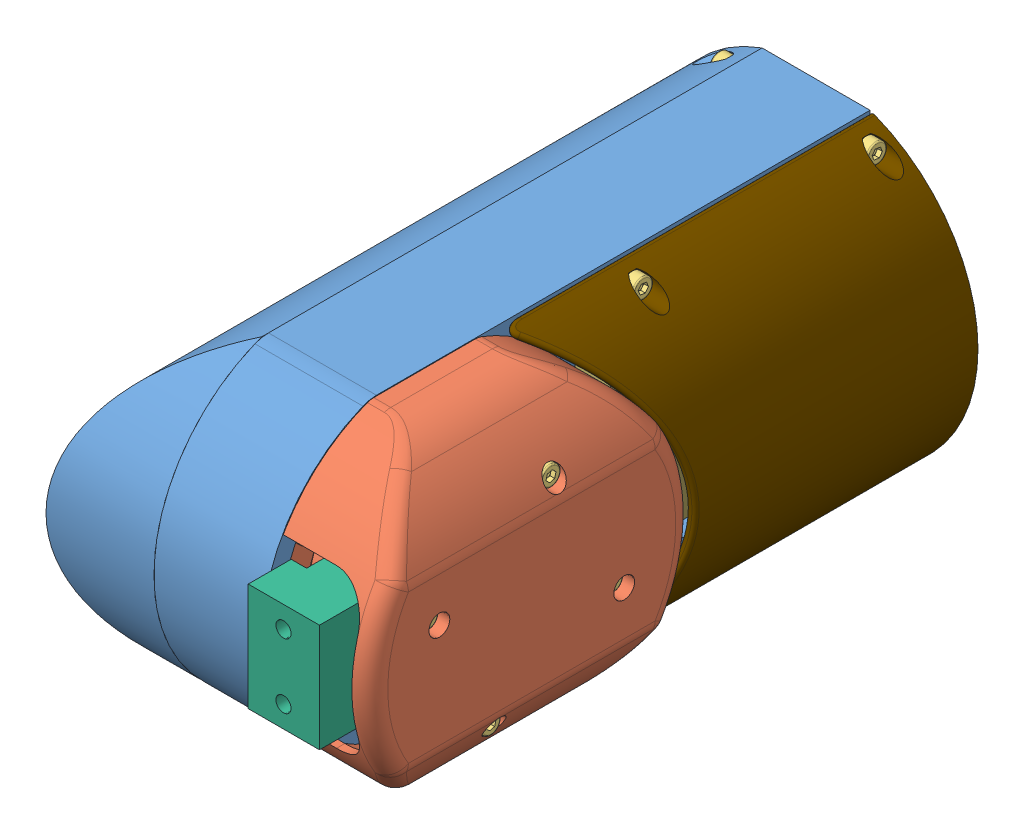
SolidWorks assembly 第二节, configuration 默认. Lengths in mm.
Overall size (169.08 108.07 185.47).
85 component instances, 22 part files, 108 mates.
Components (placement in the parent):
- 90001001-J2轴中间部件-1: 90001001-J2轴中间部件 [默认] at origin size (136.23 108.07 181.47)
- 90000013-SHF-17-80-2SH-SP刚柔轮组件-1: 90000013-SHF-17-80-2SH-SP刚柔轮组件 [默认] at (-7 0 205) x (0 1 0) z (1 0 0) size (80 80 29.5)
- hexagon socket head cap screws gb-1: hexagon socket head cap screws gb [GB_FASTENER_SCREWS_HSHCS M3X25-N] at (15 -37 205) x (-1 0 0) z (0 -0.763296 0.646049) size (28 5.5 5.5)
- hexagon socket head cap screws gb-2: hexagon socket head cap screws gb [GB_FASTENER_SCREWS_HSHCS M3X25-N] at (15 -32.0429 186.5) x (-1 0 0) z (0 -0.984058 0.177847) size (28 5.5 5.5)
- hexagon socket head cap screws gb-3: hexagon socket head cap screws gb [GB_FASTENER_SCREWS_HSHCS M3X25-N] at (15 -18.5 172.9571) x (-1 0 0) z (0 -0.941143 -0.338009) size (28 5.5 5.5)
- hexagon socket head cap screws gb-4: hexagon socket head cap screws gb [GB_FASTENER_SCREWS_HSHCS M3X25-N] at (15 0 168) x (-1 0 0) z (0 -0.646049 -0.763296) size (28 5.5 5.5)
- hexagon socket head cap screws gb-5: hexagon socket head cap screws gb [GB_FASTENER_SCREWS_HSHCS M3X25-N] at (15 18.5 172.9571) x (-1 0 0) z (0 -0.177847 -0.984058) size (28 5.5 5.5)
- hexagon socket head cap screws gb-6: hexagon socket head cap screws gb [GB_FASTENER_SCREWS_HSHCS M3X25-N] at (15 32.0429 186.5) x (-1 0 0) z (0 0.338009 -0.941143) size (28 5.5 5.5)
- hexagon socket head cap screws gb-7: hexagon socket head cap screws gb [GB_FASTENER_SCREWS_HSHCS M3X25-N] at (15 37 205) x (-1 0 0) z (0 0.763296 -0.646049) size (28 5.5 5.5)
- hexagon socket head cap screws gb-8: hexagon socket head cap screws gb [GB_FASTENER_SCREWS_HSHCS M3X25-N] at (15 32.0429 223.5) x (-1 0 0) z (0 0.984058 -0.177847) size (28 5.5 5.5)
- hexagon socket head cap screws gb-9: hexagon socket head cap screws gb [GB_FASTENER_SCREWS_HSHCS M3X25-N] at (15 18.5 237.0429) x (-1 0 0) z (0 0.941143 0.338009) size (28 5.5 5.5)
- hexagon socket head cap screws gb-10: hexagon socket head cap screws gb [GB_FASTENER_SCREWS_HSHCS M3X25-N] at (15 0 242) x (-1 0 0) z (0 0.646049 0.763296) size (28 5.5 5.5)
- hexagon socket head cap screws gb-11: hexagon socket head cap screws gb [GB_FASTENER_SCREWS_HSHCS M3X25-N] at (15 -18.5 237.0429) x (-1 0 0) z (0 0.177847 0.984058) size (28 5.5 5.5)
- hexagon socket head cap screws gb-12: hexagon socket head cap screws gb [GB_FASTENER_SCREWS_HSHCS M3X25-N] at (15 -32.0429 223.5) x (-1 0 0) z (0 -0.338009 0.941143) size (28 5.5 5.5)
- 90000013-SHF-17-80-2SH-SP波发生器-1: 90000013-SHF-17-80-2SH-SP波发生器 [默认] at (11.9 0 205) x (0 -0.338223 -0.941066) z (1 0 0) size (45 45 7.6)
- 90000009-J1轴减速机安装输出轴-1: 90000009-J1轴减速机安装输出轴 [默认] at (30.5 0 205) x (0 -0.338223 -0.941066) z (-1 0 0) size (27 27 62.5)
- hexagon socket head cap screws gb-13: hexagon socket head cap screws gb [GB_FASTENER_SCREWS_HSHCS M4X8-N] at (5.9 -3.7205 194.6483) size (12 7 7)
- hexagon socket head cap screws gb-14: hexagon socket head cap screws gb [GB_FASTENER_SCREWS_HSHCS M4X8-N] at (5.9 3.7205 215.3517) x (1 0 0) z (0 0 -1) size (12 7 7)
- 90000006-J1轴转接法兰-1: 90000006-J1轴转接法兰 [默认] at (0 0 160) x (0 -1 0) z (0 0 1) size (64 19.8 81.67)
- 90000012-轴承636-1: 90000012-轴承636 [默认] at (31 0 205) x (0 -1 0) z (-1 0 0) size (22 22 9)
- hexagon socket head cap screws gb-15: hexagon socket head cap screws gb [GB_FASTENER_SCREWS_HSHCS M3X20-N] at (30.5 15.8702 226.8435) x (-1 0 0) z (0 -0.924225 -0.381849) size (23 5.5 5.5)
- hexagon socket head cap screws gb-19: hexagon socket head cap screws gb [GB_FASTENER_SCREWS_HSHCS M3X20-N] at (30.5 21.8435 220.8702) x (-1 0 0) z (0 -0.924225 -0.381849) size (23 5.5 5.5)
- hexagon socket head cap screws gb-23: hexagon socket head cap screws gb [GB_FASTENER_SCREWS_HSHCS M3X20-N] at (30.5 25.6785 213.3435) x (-1 0 0) z (0 -0.924225 -0.381849) size (23 5.5 5.5)
- hexagon socket head cap screws gb-27: hexagon socket head cap screws gb [GB_FASTENER_SCREWS_HSHCS M3X20-N] at (30.5 27 205) x (-1 0 0) z (0 -0.924225 -0.381849) size (23 5.5 5.5)
- hexagon socket head cap screws gb-28: hexagon socket head cap screws gb [GB_FASTENER_SCREWS_HSHCS M3X20-N] at (30.5 0 178) x (-1 0 0) z (0 -0.381849 0.924225) size (23 5.5 5.5)
- hexagon socket head cap screws gb-29: hexagon socket head cap screws gb [GB_FASTENER_SCREWS_HSHCS M3X20-N] at (30.5 -27 205) x (-1 0 0) z (0 0.924225 0.381849) size (23 5.5 5.5)
- hexagon socket head cap screws gb-30: hexagon socket head cap screws gb [GB_FASTENER_SCREWS_HSHCS M3X20-N] at (30.5 0 232) x (-1 0 0) z (0 0.381849 -0.924225) size (23 5.5 5.5)
- hexagon socket head cap screws gb-24: hexagon socket head cap screws gb [GB_FASTENER_SCREWS_HSHCS M3X20-N] at (30.5 8.3435 179.3215) x (-1 0 0) z (0 -0.381849 0.924225) size (23 5.5 5.5)
- hexagon socket head cap screws gb-25: hexagon socket head cap screws gb [GB_FASTENER_SCREWS_HSHCS M3X20-N] at (30.5 -25.6785 196.6565) x (-1 0 0) z (0 0.924225 0.381849) size (23 5.5 5.5)
- hexagon socket head cap screws gb-26: hexagon socket head cap screws gb [GB_FASTENER_SCREWS_HSHCS M3X20-N] at (30.5 -8.3435 230.6785) x (-1 0 0) z (0 0.381849 -0.924225) size (23 5.5 5.5)
- hexagon socket head cap screws gb-20: hexagon socket head cap screws gb [GB_FASTENER_SCREWS_HSHCS M3X20-N] at (30.5 15.8702 183.1565) x (-1 0 0) z (0 -0.381849 0.924225) size (23 5.5 5.5)
- hexagon socket head cap screws gb-21: hexagon socket head cap screws gb [GB_FASTENER_SCREWS_HSHCS M3X20-N] at (30.5 -21.8435 189.1298) x (-1 0 0) z (0 0.924225 0.381849) size (23 5.5 5.5)
- hexagon socket head cap screws gb-22: hexagon socket head cap screws gb [GB_FASTENER_SCREWS_HSHCS M3X20-N] at (30.5 -15.8702 226.8435) x (-1 0 0) z (0 0.381849 -0.924225) size (23 5.5 5.5)
- hexagon socket head cap screws gb-16: hexagon socket head cap screws gb [GB_FASTENER_SCREWS_HSHCS M3X20-N] at (30.5 21.8435 189.1298) x (-1 0 0) z (0 -0.381849 0.924225) size (23 5.5 5.5)
- hexagon socket head cap screws gb-17: hexagon socket head cap screws gb [GB_FASTENER_SCREWS_HSHCS M3X20-N] at (30.5 -15.8702 183.1565) x (-1 0 0) z (0 0.924225 0.381849) size (23 5.5 5.5)
- hexagon socket head cap screws gb-18: hexagon socket head cap screws gb [GB_FASTENER_SCREWS_HSHCS M3X20-N] at (30.5 -21.8435 220.8702) x (-1 0 0) z (0 0.381849 -0.924225) size (23 5.5 5.5)
- 90000010-J1轴减速机安装法兰-1: 90000010-J1轴减速机安装法兰 [默认] at (-15.5 0 205) x (0 0 -1) z (1 0 0) size (64 64 12.5)
- hexagon socket head cap screws gb-31: hexagon socket head cap screws gb [GB_FASTENER_SCREWS_HSHCS M3X8-N] at (-18.5 0 176) size (11 5.5 5.5)
- hexagon socket head cap screws gb-32: hexagon socket head cap screws gb [GB_FASTENER_SCREWS_HSHCS M3X8-N] at (-18.5 -20.5061 184.4939) x (1 0 0) z (0 0.707107 0.707107) size (11 5.5 5.5)
- hexagon socket head cap screws gb-33: hexagon socket head cap screws gb [GB_FASTENER_SCREWS_HSHCS M3X8-N] at (-18.5 -29 205) x (1 0 0) z (0 1 0) size (11 5.5 5.5)
- hexagon socket head cap screws gb-34: hexagon socket head cap screws gb [GB_FASTENER_SCREWS_HSHCS M3X8-N] at (-18.5 -20.5061 225.5061) x (1 0 0) z (0 0.707107 -0.707107) size (11 5.5 5.5)
- hexagon socket head cap screws gb-35: hexagon socket head cap screws gb [GB_FASTENER_SCREWS_HSHCS M3X8-N] at (-18.5 0 234) x (1 0 0) z (0 0 -1) size (11 5.5 5.5)
- hexagon socket head cap screws gb-36: hexagon socket head cap screws gb [GB_FASTENER_SCREWS_HSHCS M3X8-N] at (-18.5 20.5061 225.5061) x (1 0 0) z (0 -0.707107 -0.707107) size (11 5.5 5.5)
- hexagon socket head cap screws gb-37: hexagon socket head cap screws gb [GB_FASTENER_SCREWS_HSHCS M3X8-N] at (-18.5 29 205) x (1 0 0) z (0 -1 0) size (11 5.5 5.5)
- hexagon socket head cap screws gb-38: hexagon socket head cap screws gb [GB_FASTENER_SCREWS_HSHCS M3X8-N] at (-18.5 20.5061 184.4939) x (1 0 0) z (0 -0.707107 0.707107) size (11 5.5 5.5)
- 90000022-NOK油封AE0090A0-1: 90000022-NOK油封AE0090A0 [默认] at (-15.5 0 205) x (0 0 -1) z (1 0 0) size (20 20 7)
- 90000011-轴承638-1: 90000011-轴承638 [默认] at (-8.5 0 205) x (0 0 -1) z (1 0 0) size (28 28 9)
- 90000005-J1轴电机安装板-1: 90000005-J1轴电机安装板 [默认] at (-7 0 133) x (0 1 0) z (-1 0 0) size (70 42 2.2)
- 90000015-汉德宝1701HS06AX-1: 90000015-汉德宝1701HS06AX [默认] at (24 0 133) x (0 0 1) z (-1 0 0) size (42.3 42.3 55)
- hexagon socket head cap screws gb-39: hexagon socket head cap screws gb [GB_FASTENER_SCREWS_HSHCS M3X8-N] at (-12.2 32 117.5) size (11 5.5 5.5)
- hexagon socket head cap screws gb-40: hexagon socket head cap screws gb [GB_FASTENER_SCREWS_HSHCS M3X8-N] at (-12.2 15.5 117.5) x (1 0 0) z (0 0 -1) size (11 5.5 5.5)
- hexagon socket head cap screws gb-44: hexagon socket head cap screws gb [GB_FASTENER_SCREWS_HSHCS M3X8-N] at (-12.2 32 148.5) x (1 0 0) z (0 0 -1) size (11 5.5 5.5)
- hexagon socket head cap screws gb-45: hexagon socket head cap screws gb [GB_FASTENER_SCREWS_HSHCS M3X8-N] at (-12.2 -32 148.5) x (1 0 0) z (0 0 -1) size (11 5.5 5.5)
- hexagon socket head cap screws gb-46: hexagon socket head cap screws gb [GB_FASTENER_SCREWS_HSHCS M3X8-N] at (-12.2 -32 117.5) x (1 0 0) z (0 0 -1) size (11 5.5 5.5)
- hexagon socket head cap screws gb-41: hexagon socket head cap screws gb [GB_FASTENER_SCREWS_HSHCS M3X8-N] at (-12.2 15.5 148.5) x (1 0 0) z (0 1 0) size (11 5.5 5.5)
- hexagon socket head cap screws gb-42: hexagon socket head cap screws gb [GB_FASTENER_SCREWS_HSHCS M3X8-N] at (-12.2 -15.5 148.5) size (11 5.5 5.5)
- hexagon socket head cap screws gb-43: hexagon socket head cap screws gb [GB_FASTENER_SCREWS_HSHCS M3X8-N] at (-12.2 -15.5 117.5) x (1 0 0) z (0 -1 0) size (11 5.5 5.5)
- 90000014-BXR-020-10E抱闸-1: 90000014-BXR-020-10E抱闸 [默认] at (-9.2 0 133) x (0 0.866025 -0.5) z (-1 0 0) size (32 32 14)
- 90000008-3GT-24齿-6减速机端同步带轮-1: 90000008-3GT-24齿-6减速机端同步带轮 [默认] at (-23 0 205) x (0 -0.941066 0.338223) z (-1 0 0) size (35.8 35.8 14)
- hex socket set screws with flat point gb-1: hex socket set screws with flat point gb [GB_FASTENER_SCREWS_HSFP M4X5-N] at (-27.5 2.5367 212.058) x (0 -0.338223 -0.941066) z (0.939161 0.323236 -0.116172) size (5 4 4)
- hex socket set screws with flat point gb-2: hex socket set screws with flat point gb [GB_FASTENER_SCREWS_HSFP M4X5-N] at (-27.5 -7.058 207.5367) x (0 0.941066 -0.338223) z (0.055448 -0.337703 -0.939618) size (5 4 4)
- 90000007-3GT-24齿-6同步带轮-1: 90000007-3GT-24齿-6同步带轮 [默认] at (-25.4 0 133) x (0 1 0) z (-1 0 0) size (29.8 29.8 8)
- hex socket set screws with flat point gb-3: hex socket set screws with flat point gb [GB_FASTENER_SCREWS_HSFP M4X5-N] at (-27.4 0 126) x (0 0 1) z (0.939161 -0.343478 0) size (5 4 4)
- 90000023-240-3GT-6-1: 90000023-240-3GT-6 [默认] at (-30.4 0 133) x (0 0 1) z (1 0 0) size (104.36 32.36 6)
- 90000003-底座中间部件左端盖-1: 90000003-底座中间部件左端盖 [默认] at (0 0 81) x (0 -1 0) z (0 0 1) size (84.36 33.92 105.12)
- 90000004-底座中间部件右端盖-1: 90000004-底座中间部件右端盖 [默认] at (0 0 250) x (0 -1 0) z (0 0 -1) size (84.85 31.21 169)
- hexagon socket head cap screws gb-47: hexagon socket head cap screws gb [GB_FASTENER_SCREWS_HSHCS M3X8-N] at (22 38 86) x (-1 0 0) z (0 -0.924225 -0.381849) size (11 5.5 5.5)
- hexagon socket head cap screws gb-48: hexagon socket head cap screws gb [GB_FASTENER_SCREWS_HSHCS M3X8-N] at (22 38 151) x (-1 0 0) z (0 -0.924225 -0.381849) size (11 5.5 5.5)
- hexagon socket head cap screws gb-49: hexagon socket head cap screws gb [GB_FASTENER_SCREWS_HSHCS M3X8-N] at (22 -38 151) x (-1 0 0) z (0 -0.924225 -0.381849) size (11 5.5 5.5)
- hexagon socket head cap screws gb-50: hexagon socket head cap screws gb [GB_FASTENER_SCREWS_HSHCS M3X8-N] at (22 -38 86) x (-1 0 0) z (0 -0.924225 -0.381849) size (11 5.5 5.5)
- hexagon socket head cap screws gb-51: hexagon socket head cap screws gb [GB_FASTENER_SCREWS_HSHCS M3X8-N] at (-22 38 86) x (1 0 0) z (0 0 -1) size (11 5.5 5.5)
- hexagon socket head cap screws gb-52: hexagon socket head cap screws gb [GB_FASTENER_SCREWS_HSHCS M3X8-N] at (-22 -38 86) x (1 0 0) z (0 0 -1) size (11 5.5 5.5)
- hexagon socket head cap screws gb-53: hexagon socket head cap screws gb [GB_FASTENER_SCREWS_HSHCS M3X8-N] at (-22 0 246) size (11 5.5 5.5)
- 90000024-底座法兰端盖-1: 90000024-底座法兰端盖 [默认] at (0 0 160) x (0 -1 0) z (0 0 1) size (86.96 29.8 90)
- hexagon socket head cap screws gb-54: hexagon socket head cap screws gb [GB_FASTENER_SCREWS_HSHCS M3X8-N] at (42 -8.3435 179.3215) x (-1 0 0) z (0 -0.699059 0.715064) size (11 5.5 5.5)
- hexagon socket head cap screws gb-55: hexagon socket head cap screws gb [GB_FASTENER_SCREWS_HSHCS M3X8-N] at (42 25.6785 196.6565) x (-1 0 0) z (0 -0.715064 -0.699059) size (11 5.5 5.5)
- hexagon socket head cap screws gb-56: hexagon socket head cap screws gb [GB_FASTENER_SCREWS_HSHCS M3X8-N] at (42 8.3435 230.6785) x (-1 0 0) z (0 0.699059 -0.715064) size (11 5.5 5.5)
- hexagon socket head cap screws gb-57: hexagon socket head cap screws gb [GB_FASTENER_SCREWS_HSHCS M3X8-N] at (42 -25.6785 213.3435) x (-1 0 0) z (0 0.715064 0.699059) size (11 5.5 5.5)
- 90000025-PCBboard安装柱-1: 90000025-PCBboard安装柱 [默认] at (0 -25 99.5) x (-0.923728 -0.383049 0) z (0 0 -1) size (5 6 10)
- 90000025-PCBboard安装柱-2: 90000025-PCBboard安装柱 [默认] at (0 25 99.5) x (-0.923728 -0.383049 0) z (0 0 -1) size (5 6 10)
- hexagon socket head cap screws gb-59: hexagon socket head cap screws gb [GB_FASTENER_SCREWS_HSHCS M5X20-N] at (9 25 99) x (0 0 -1) z (1 0 0) size (25 8.5 8.5)
- hexagon socket head cap screws gb-60: hexagon socket head cap screws gb [GB_FASTENER_SCREWS_HSHCS M5X20-N] at (-9 25 99) x (0 0 -1) z (1 0 0) size (25 8.5 8.5)
- 90000026-PCBboard-1: 90000026-PCBboard [默认] at (0 0 99.5) x (0 1 0) z (0 0 1) size (65 70 5)
- hexagon socket head cap screws gb-61: hexagon socket head cap screws gb [GB_FASTENER_SCREWS_HSHCS M3X8-N] at (0 25 107.5) x (0 0 -1) z (-0.706748 0.707465 0) size (11 5.5 5.5)
- hexagon socket head cap screws gb-62: hexagon socket head cap screws gb [GB_FASTENER_SCREWS_HSHCS M3X8-N] at (0 -25 107.5) x (0 0 -1) z (-0.706748 0.707465 0) size (11 5.5 5.5)
Mates (geometry in assembly coordinates):
- 重合1: coincident aligned: plane of 90001001-J2轴中间部件-1 through (0 0 0) normal (0 0 1); plane of assembly through (0 0 0) normal (0 0 1)
- 重合2: coincident aligned: plane of 90001001-J2轴中间部件-1 through (0 0 0) normal (0 1 0); plane of assembly through (0 0 0) normal (0 1 0)
- 重合3: coincident aligned: plane of 90001001-J2轴中间部件-1 through (0 0 0) normal (1 0 0); plane of assembly through (0 0 0) normal (1 0 0)
- 同心1: concentric anti-aligned: cylinder of 90001001-J2轴中间部件-1 through (-7 0 205) axis (1 0 0) radius 40; cylinder of 90000013-SHF-17-80-2SH-SP刚柔轮组件-1 through (19.5 0 205) axis (-1 0 0) radius 40
- 同心2: concentric aligned: circle of 90001001-J2轴中间部件-1; cylinder of 90000013-SHF-17-80-2SH-SP刚柔轮组件-1 through (-10 -26.163 178.837) axis (1 0 0) radius 2.75
- 重合4: coincident anti-aligned: plane of 90001001-J2轴中间部件-1 through (-7 0 205) normal (1 0 0); plane of 90000013-SHF-17-80-2SH-SP刚柔轮组件-1 through (-7 0 205) normal (-1 0 0)
- 同心4: concentric aligned: cylinder of 90000013-SHF-17-80-2SH-SP刚柔轮组件-1 through (-47.5 -37 205) axis (1 0 0) radius 1.75; cylinder of hexagon socket head cap screws gb-1 through (-13 -37 205) axis (1 0 0) radius 1.5
- 重合5: coincident anti-aligned: plane of 90000013-SHF-17-80-2SH-SP刚柔轮组件-1 through (12 0 205) normal (1 0 0); plane of hexagon socket head cap screws gb-1 through (12 -37 205) normal (-1 0 0)
- 同心5: concentric anti-aligned: cylinder of 90000013-SHF-17-80-2SH-SP刚柔轮组件-1 through (-40 0 205) axis (1 0 0) radius 22.5; cylinder of 90000013-SHF-17-80-2SH-SP波发生器-1 through (19.5 0 205) axis (-1 0 0) radius 22.5
- 重合6: coincident aligned: plane of 90000013-SHF-17-80-2SH-SP刚柔轮组件-1 through (19.5 0 205) normal (1 0 0); plane of 90000013-SHF-17-80-2SH-SP波发生器-1 through (19.5 0 205) normal (1 0 0)
- 同心6: concentric anti-aligned: cylinder of 90000013-SHF-17-80-2SH-SP波发生器-1 through (19.5 0 205) axis (-1 0 0) radius 4; cylinder of 90000009-J1轴减速机安装输出轴-1 through (-20.5 0 205) axis (1 0 0) radius 4
- 同心7: concentric aligned: cylinder of 90000013-SHF-17-80-2SH-SP波发生器-1 through (19.5 -3.7205 194.6483) axis (1 0 0) radius 1.65; circle of 90000009-J1轴减速机安装输出轴-1
- 重合7: coincident anti-aligned: plane of 90000013-SHF-17-80-2SH-SP波发生器-1 through (11.9 0 205) normal (-1 0 0); plane of 90000009-J1轴减速机安装输出轴-1 through (11.9 0 205) normal (1 0 0)
- 同心8: concentric anti-aligned: cylinder of 90000013-SHF-17-80-2SH-SP波发生器-1 through (19.5 -3.7205 194.6483) axis (1 0 0) radius 1.65; cylinder of hexagon socket head cap screws gb-13 through (17.9 -3.7205 194.6483) axis (-1 0 0) radius 2
- 重合8: coincident anti-aligned: plane of 90000009-J1轴减速机安装输出轴-1 through (9.9 0 205) normal (-1 0 0); plane of hexagon socket head cap screws gb-13 through (9.9 -3.7205 194.6483) normal (1 0 0)
- 同心9: concentric anti-aligned: cylinder of 90000006-J1轴转接法兰-1 through (31.5 0 205) axis (-1 0 0) radius 11; cylinder of 90000012-轴承636-1 through (22 0 205) axis (1 0 0) radius 11
- 重合9: coincident anti-aligned: plane of 90000006-J1轴转接法兰-1 through (31 0 205) normal (-1 0 0); plane of 90000012-轴承636-1 through (31 0 205) normal (1 0 0)
- 同心10: concentric aligned: cylinder of 90000009-J1轴减速机安装输出轴-1 through (22 0 205) axis (1 0 0) radius 3; cylinder of 90000012-轴承636-1 through (22 0 205) axis (1 0 0) radius 3
- 同心12: concentric aligned: cylinder of 90000013-SHF-17-80-2SH-SP刚柔轮组件-1 through (19.5 0 232) axis (1 0 0) radius 1.25; cylinder of 90000006-J1轴转接法兰-1 through (27.5 0 232) axis (1 0 0) radius 3
- 重合10: coincident anti-aligned: plane of 90000013-SHF-17-80-2SH-SP刚柔轮组件-1 through (19.5 0 205) normal (1 0 0); plane of 90000006-J1轴转接法兰-1 through (19.5 0 205) normal (-1 0 0)
- 同心13: concentric aligned: cylinder of 90000006-J1轴转接法兰-1 through (27.5 15.8702 226.8435) axis (1 0 0) radius 3; cylinder of hexagon socket head cap screws gb-15 through (7.5 15.8702 226.8435) axis (1 0 0) radius 1.5
- 重合11: coincident anti-aligned: plane of 90000006-J1轴转接法兰-1 through (27.5 15.8702 226.8435) normal (1 0 0); plane of hexagon socket head cap screws gb-15 through (27.5 15.8702 226.8435) normal (-1 0 0)
- 同心14: concentric aligned: cylinder of 90000006-J1轴转接法兰-1 through (-15 21.8435 220.8702) axis (1 0 0) radius 1.7; cylinder of hexagon socket head cap screws gb-19 through (7.5 21.8435 220.8702) axis (1 0 0) radius 1.5
- 重合12: coincident anti-aligned: plane of 90000006-J1轴转接法兰-1 through (27.5 21.8435 220.8702) normal (1 0 0); plane of hexagon socket head cap screws gb-19 through (27.5 21.8435 220.8702) normal (-1 0 0)
- 同心15: concentric aligned: cylinder of 90000006-J1轴转接法兰-1 through (-15 25.6785 213.3435) axis (1 0 0) radius 1.7; cylinder of hexagon socket head cap screws gb-23 through (7.5 25.6785 213.3435) axis (1 0 0) radius 1.5
- 重合13: coincident anti-aligned: plane of 90000006-J1轴转接法兰-1 through (27.5 25.6785 213.3435) normal (1 0 0); plane of hexagon socket head cap screws gb-23 through (27.5 25.6785 213.3435) normal (-1 0 0)
- 同心16: concentric aligned: cylinder of 90000006-J1轴转接法兰-1 through (-15 27 205) axis (1 0 0) radius 1.7; cylinder of hexagon socket head cap screws gb-27 through (7.5 27 205) axis (1 0 0) radius 1.5
- 重合14: coincident anti-aligned: plane of 90000006-J1轴转接法兰-1 through (27.5 27 205) normal (1 0 0); plane of hexagon socket head cap screws gb-27 through (27.5 27 205) normal (-1 0 0)
- 同心17: concentric anti-aligned: cylinder of 90001001-J2轴中间部件-1 through (-29 0 205) axis (1 0 0) radius 23; cylinder of 90000010-J1轴减速机安装法兰-1 through (-8.5 0 205) axis (-1 0 0) radius 10
- 同心18: concentric anti-aligned: cylinder of 90001001-J2轴中间部件-1 through (-11 20.5061 225.5061) axis (-1 0 0) radius 1.25; cylinder of 90000010-J1轴减速机安装法兰-1 through (-21 20.5061 225.5061) axis (1 0 0) radius 1.7
- 重合15: coincident anti-aligned: plane of 90001001-J2轴中间部件-1 through (-11 0 205) normal (-1 0 0); plane of 90000010-J1轴减速机安装法兰-1 through (-11 0 205) normal (1 0 0)
- 同心19: concentric anti-aligned: cylinder of 90000010-J1轴减速机安装法兰-1 through (-21 0 176) axis (1 0 0) radius 1.7; cylinder of hexagon socket head cap screws gb-31 through (-7.5 0 176) axis (-1 0 0) radius 1.5
- 重合16: coincident anti-aligned: plane of 90000010-J1轴减速机安装法兰-1 through (-15.5 0 205) normal (-1 0 0); plane of hexagon socket head cap screws gb-31 through (-15.5 0 176) normal (1 0 0)
- 同心20: concentric anti-aligned: cylinder of 90000010-J1轴减速机安装法兰-1 through (-8.5 0 205) axis (-1 0 0) radius 10; cylinder of 90000022-NOK油封AE0090A0-1 through (-12.5 0 205) axis (1 0 0) radius 9
- 重合17: coincident aligned: plane of 90000010-J1轴减速机安装法兰-1 through (-15.5 0 205) normal (-1 0 0); plane of 90000022-NOK油封AE0090A0-1 through (-15.5 0 205) normal (-1 0 0)
- 同心21: concentric anti-aligned: cylinder of 90000010-J1轴减速机安装法兰-1 through (-15.5 0 205) axis (1 0 0) radius 14; cylinder of 90000011-轴承638-1 through (0.5 0 205) axis (-1 0 0) radius 14
- 重合18: coincident anti-aligned: plane of 90000010-J1轴减速机安装法兰-1 through (-8.5 0 205) normal (1 0 0); plane of 90000011-轴承638-1 through (-8.5 0 205) normal (-1 0 0)
- 同心22: concentric anti-aligned: cylinder of 90001001-J2轴中间部件-1 through (-15 -32 148.5) axis (-1 0 0) radius 1.25; cylinder of 90000005-J1轴电机安装板-1 through (-9.2 -32 148.5) axis (1 0 0) radius 1.75
- 同心23: concentric anti-aligned: cylinder of 90001001-J2轴中间部件-1 through (-15 -32 117.5) axis (-1 0 0) radius 1.25; cylinder of 90000005-J1轴电机安装板-1 through (-9.2 -32 117.5) axis (1 0 0) radius 1.75
- 重合19: coincident anti-aligned: plane of 90001001-J2轴中间部件-1 through (-7 0 0) normal (-1 0 0); plane of 90000005-J1轴电机安装板-1 through (-7 0 133) normal (1 0 0)
- 同心24: concentric aligned: cylinder of 90000005-J1轴电机安装板-1 through (-9.2 0 133) axis (1 0 0) radius 11.5; cylinder of 90000015-汉德宝1701HS06AX-1 through (-9 0 133) axis (1 0 0) radius 11
- 同心25: concentric aligned: cylinder of 90000005-J1轴电机安装板-1 through (0.8 -15.5 148.5) axis (-1 0 0) radius 1.75; cylinder of 90000015-汉德宝1701HS06AX-1 through (-7 -15.5 148.5) axis (-1 0 0) radius 1.25
- 重合20: coincident anti-aligned: plane of 90000005-J1轴电机安装板-1 through (-7 0 133) normal (1 0 0); plane of 90000015-汉德宝1701HS06AX-1 through (-7 0 133) normal (-1 0 0)
- 同心26: concentric anti-aligned: cylinder of 90000005-J1轴电机安装板-1 through (-9.2 32 117.5) axis (1 0 0) radius 1.75; cylinder of hexagon socket head cap screws gb-39 through (-1.2 32 117.5) axis (-1 0 0) radius 1.5
- 重合21: coincident anti-aligned: plane of 90000005-J1轴电机安装板-1 through (-9.2 0 133) normal (-1 0 0); plane of hexagon socket head cap screws gb-39 through (-9.2 32 117.5) normal (1 0 0)
- 同心27: concentric aligned: cylinder of 90000015-汉德宝1701HS06AX-1 through (-7 15.5 117.5) axis (-1 0 0) radius 1.25; cylinder of hexagon socket head cap screws gb-40 through (-1.2 15.5 117.5) axis (-1 0 0) radius 1.5
- 重合22: coincident anti-aligned: plane of 90000005-J1轴电机安装板-1 through (-9.2 0 133) normal (-1 0 0); plane of hexagon socket head cap screws gb-40 through (-9.2 15.5 117.5) normal (1 0 0)
- 同心28: concentric aligned: cylinder of 90001001-J2轴中间部件-1 through (-15 32 148.5) axis (-1 0 0) radius 1.25; cylinder of hexagon socket head cap screws gb-44 through (-1.2 32 148.5) axis (-1 0 0) radius 1.5
- 重合23: coincident anti-aligned: plane of 90000005-J1轴电机安装板-1 through (-9.2 0 133) normal (-1 0 0); plane of hexagon socket head cap screws gb-44 through (-9.2 32 148.5) normal (1 0 0)
- 同心29: concentric aligned: cylinder of 90001001-J2轴中间部件-1 through (-15 -32 148.5) axis (-1 0 0) radius 1.25; cylinder of hexagon socket head cap screws gb-45 through (-1.2 -32 148.5) axis (-1 0 0) radius 1.5
- 重合24: coincident anti-aligned: plane of 90000005-J1轴电机安装板-1 through (-9.2 0 133) normal (-1 0 0); plane of hexagon socket head cap screws gb-45 through (-9.2 -32 148.5) normal (1 0 0)
- 同心30: concentric aligned: cylinder of 90001001-J2轴中间部件-1 through (-15 -32 117.5) axis (-1 0 0) radius 1.25; cylinder of hexagon socket head cap screws gb-46 through (-1.2 -32 117.5) axis (-1 0 0) radius 1.5
- 重合25: coincident anti-aligned: plane of 90000005-J1轴电机安装板-1 through (-9.2 0 133) normal (-1 0 0); plane of hexagon socket head cap screws gb-46 through (-9.2 -32 117.5) normal (1 0 0)
- 同心33: concentric anti-aligned: cylinder of 90000009-J1轴减速机安装输出轴-1 through (-18 0 205) axis (-1 0 0) radius 3; cylinder of 90000008-3GT-24齿-6减速机端同步带轮-1 through (-34 0 205) axis (1 0 0) radius 3
- 同心34: concentric aligned: cylinder of 90000008-3GT-24齿-6减速机端同步带轮-1 through (-27.5 5.0733 219.116) axis (0 0.338223 0.941066) radius 1.65; cylinder of hex socket set screws with flat point gb-1 through (-27.5 6.1709 222.1698) axis (0 0.338223 0.941066) radius 2
- 重合28: coincident anti-aligned: plane of 90000009-J1轴减速机安装输出轴-1 through (-19 5.5509 205.6616) normal (0 0.338223 0.941066); plane of hex socket set screws with flat point gb-1 through (-27.5 0.8456 207.3527) normal (0 -0.338223 -0.941066)
- 重合29: coincident aligned: plane of 90000009-J1轴减速机安装输出轴-1 through (-32 0 205) normal (-1 0 0); plane of 90000008-3GT-24齿-6减速机端同步带轮-1 through (-32 0 205) normal (-1 0 0)
- 同心35: concentric aligned: cylinder of 90000008-3GT-24齿-6减速机端同步带轮-1 through (-27.5 -14.116 210.0733) axis (0 -0.941066 0.338223) radius 1.65; cylinder of hex socket set screws with flat point gb-2 through (-27.5 -17.1698 211.1709) axis (0 -0.941066 0.338223) radius 2
- 重合30: coincident anti-aligned: plane of 90000009-J1轴减速机安装输出轴-1 through (-19 -0.6616 210.5509) normal (0 -0.941066 0.338223); plane of hex socket set screws with flat point gb-2 through (-27.5 -2.3527 205.8456) normal (0 0.941066 -0.338223)
- 重合31: coincident anti-aligned: plane of 90000015-汉德宝1701HS06AX-1 through (-10 -5 131) normal (0 0 -1); plane of hex socket set screws with flat point gb-3 through (-27.4 0 131) normal (0 0 1)
- 同心38: concentric anti-aligned: cylinder of 90000008-3GT-24齿-6减速机端同步带轮-1 through (-32 0 205) axis (1 0 0) radius 14.9; cylinder of 90000023-240-3GT-6-1 through (-24.4 0 205) axis (-1 0 0) radius 14.9
- 同心39: concentric anti-aligned: cylinder of 90001001-J2轴中间部件-1 through (15 38 86) axis (1 0 0) radius 1.25; cylinder of 90000003-底座中间部件左端盖-1 through (515 38 86) axis (-1 0 0) radius 1.7
- 同心40: concentric anti-aligned: cylinder of 90001001-J2轴中间部件-1 through (15 -38 86) axis (1 0 0) radius 1.25; cylinder of 90000003-底座中间部件左端盖-1 through (515 -38 86) axis (-1 0 0) radius 1.7
- 重合35: coincident anti-aligned: plane of 90001001-J2轴中间部件-1 through (15 -124 100) normal (1 0 0); plane of 90000003-底座中间部件左端盖-1 through (15 0 81) normal (-1 0 0)
- 同心41: concentric aligned: cylinder of 90001001-J2轴中间部件-1 through (-15 0 246) axis (-1 0 0) radius 1.25; cylinder of 90000004-底座中间部件右端盖-1 through (-19 0 246) axis (-1 0 0) radius 3
- 同心42: concentric aligned: cylinder of 90001001-J2轴中间部件-1 through (-15 -38 86) axis (-1 0 0) radius 1.25; cylinder of 90000004-底座中间部件右端盖-1 through (0 -38 86) axis (-1 0 0) radius 1.7
- 重合36: coincident anti-aligned: plane of 90001001-J2轴中间部件-1 through (-15 -124 100) normal (-1 0 0); plane of 90000004-底座中间部件右端盖-1 through (-15 0 250) normal (1 0 0)
- 同心44: concentric anti-aligned: cylinder of 90000003-底座中间部件左端盖-1 through (515 38 86) axis (-1 0 0) radius 1.7; cylinder of hexagon socket head cap screws gb-47 through (11 38 86) axis (1 0 0) radius 1.5
- 重合37: coincident anti-aligned: plane of 90000003-底座中间部件左端盖-1 through (19 0 81) normal (1 0 0); plane of hexagon socket head cap screws gb-47 through (19 38 86) normal (-1 0 0)
- 同心45: concentric anti-aligned: cylinder of 90000003-底座中间部件左端盖-1 through (515 38 151) axis (-1 0 0) radius 1.7; cylinder of hexagon socket head cap screws gb-48 through (11 38 151) axis (1 0 0) radius 1.5
- 重合38: coincident anti-aligned: plane of 90000003-底座中间部件左端盖-1 through (19 0 81) normal (1 0 0); plane of hexagon socket head cap screws gb-48 through (19 38 151) normal (-1 0 0)
- 同心46: concentric anti-aligned: cylinder of 90000003-底座中间部件左端盖-1 through (515 -38 151) axis (-1 0 0) radius 1.7; cylinder of hexagon socket head cap screws gb-49 through (11 -38 151) axis (1 0 0) radius 1.5
- 重合39: coincident anti-aligned: plane of 90000003-底座中间部件左端盖-1 through (19 0 81) normal (1 0 0); plane of hexagon socket head cap screws gb-49 through (19 -38 151) normal (-1 0 0)
- 同心47: concentric anti-aligned: cylinder of 90000003-底座中间部件左端盖-1 through (515 -38 86) axis (-1 0 0) radius 1.7; cylinder of hexagon socket head cap screws gb-50 through (11 -38 86) axis (1 0 0) radius 1.5
- 重合40: coincident anti-aligned: plane of 90000003-底座中间部件左端盖-1 through (19 0 81) normal (1 0 0); plane of hexagon socket head cap screws gb-50 through (19 -38 86) normal (-1 0 0)
- 同心48: concentric aligned: cylinder of 90000004-底座中间部件右端盖-1 through (0 38 86) axis (-1 0 0) radius 1.7; cylinder of hexagon socket head cap screws gb-51 through (-11 38 86) axis (-1 0 0) radius 1.5
- 重合41: coincident anti-aligned: plane of 90000004-底座中间部件右端盖-1 through (-19 38 86) normal (-1 0 0); plane of hexagon socket head cap screws gb-51 through (-19 38 86) normal (1 0 0)
- 同心49: concentric aligned: cylinder of 90000004-底座中间部件右端盖-1 through (0 -38 86) axis (-1 0 0) radius 1.7; cylinder of hexagon socket head cap screws gb-52 through (-11 -38 86) axis (-1 0 0) radius 1.5
- 重合42: coincident anti-aligned: plane of 90000004-底座中间部件右端盖-1 through (-19 -38 86) normal (-1 0 0); plane of hexagon socket head cap screws gb-52 through (-19 -38 86) normal (1 0 0)
- 同心50: concentric anti-aligned: cylinder of 90000004-底座中间部件右端盖-1 through (-65 0 246) axis (1 0 0) radius 1.7; cylinder of hexagon socket head cap screws gb-53 through (-11 0 246) axis (-1 0 0) radius 1.5
- 重合43: coincident anti-aligned: plane of 90000004-底座中间部件右端盖-1 through (-19 0 246) normal (-1 0 0); plane of hexagon socket head cap screws gb-53 through (-19 0 246) normal (1 0 0)
- 同心51: concentric anti-aligned: cylinder of 90000015-汉德宝1701HS06AX-1 through (-31 0 133) axis (1 0 0) radius 2.5; cylinder of 90000014-BXR-020-10E抱闸-1 through (-9.2 0 133) axis (-1 0 0) radius 4.5
- 重合44: coincident anti-aligned: plane of 90000005-J1轴电机安装板-1 through (-9.2 0 133) normal (-1 0 0); plane of 90000014-BXR-020-10E抱闸-1 through (-9.2 -5.9267 155.1187) normal (1 0 0)
- 同心52: concentric anti-aligned: circle of 90000005-J1轴电机安装板-1; circle of 90000014-BXR-020-10E抱闸-1
- 同心53: concentric anti-aligned: cylinder of 90000015-汉德宝1701HS06AX-1 through (-31 0 133) axis (1 0 0) radius 2.5; cylinder of 90000007-3GT-24齿-6同步带轮-1 through (-31.4 0 133) axis (-1 0 0) radius 2.5
- 距离1: distance = 0.2 mm anti-aligned: plane of 90000007-3GT-24齿-6同步带轮-1 through (-23.4 0 133) normal (1 0 0); plane of 90000014-BXR-020-10E抱闸-1 through (-23.2 -5.9273 155.1177) normal (-1 0 0)
- 同心54: concentric aligned: cylinder of 90000007-3GT-24齿-6同步带轮-1 through (-23.4 0 133) axis (-1 0 0) radius 14.9; cylinder of 90000023-240-3GT-6-1 through (-24.4 0 133) axis (-1 0 0) radius 14.9
- 距离2: distance = 1 mm aligned: plane of 90000023-240-3GT-6-1 through (-24.4 0 205) normal (1 0 0); plane of 90000007-3GT-24齿-6同步带轮-1 through (-23.4 0 133) normal (1 0 0)
- 同心55: concentric aligned: cylinder of 90000006-J1轴转接法兰-1 through (35 -25.6785 213.3435) axis (1 0 0) radius 1.25; cylinder of 90000024-底座法兰端盖-1 through (39 -25.6785 213.3435) axis (1 0 0) radius 2.9
- 同心56: concentric aligned: cylinder of 90000006-J1轴转接法兰-1 through (35 8.3435 230.6785) axis (1 0 0) radius 1.25; cylinder of 90000024-底座法兰端盖-1 through (39 8.3435 230.6785) axis (1 0 0) radius 2.9
- 重合45: coincident anti-aligned: plane of 90000006-J1轴转接法兰-1 through (35 100 251) normal (1 0 0); plane of 90000024-底座法兰端盖-1 through (35 0 205) normal (-1 0 0)
- 同心57: concentric aligned: cylinder of 90000024-底座法兰端盖-1 through (39 -8.3435 179.3215) axis (1 0 0) radius 2.9; cylinder of hexagon socket head cap screws gb-54 through (31 -8.3435 179.3215) axis (1 0 0) radius 1.5
- 重合47: coincident anti-aligned: plane of 90000024-底座法兰端盖-1 through (39 -8.3435 179.3215) normal (1 0 0); circle of hexagon socket head cap screws gb-54
- 同心58: concentric anti-aligned: cylinder of 90001001-J2轴中间部件-1 through (0 -25 99) axis (0 0 1) radius 1.25; cylinder of 90000025-PCBboard安装柱-1 through (0 -25 94) axis (0 0 -1) radius 1.5
- 重合48: coincident anti-aligned: plane of 90001001-J2轴中间部件-1 through (-15 -33 94) normal (0 0 1); plane of 90000025-PCBboard安装柱-1 through (0 -25 94) normal (0 0 -1)
- 同心59: concentric anti-aligned: cylinder of 90001001-J2轴中间部件-1 through (0 25 99) axis (0 0 1) radius 1.25; cylinder of 90000025-PCBboard安装柱-2 through (0 25 94) axis (0 0 -1) radius 1.5
- 重合49: coincident anti-aligned: plane of 90001001-J2轴中间部件-1 through (-15 -33 94) normal (0 0 1); plane of 90000025-PCBboard安装柱-2 through (0 25 94) normal (0 0 -1)
- 同心61: concentric anti-aligned: cylinder of 90001001-J2轴中间部件-1 through (9 25 104) axis (0 0 -1) radius 2.75; cylinder of hexagon socket head cap screws gb-59 through (9 25 74) axis (0 0 1) radius 2.5
- 重合50: coincident anti-aligned: plane of 90001001-J2轴中间部件-1 through (-15 -33 94) normal (0 0 1); plane of hexagon socket head cap screws gb-59 through (9 25 94) normal (0 0 -1)
- 同心62: concentric anti-aligned: cylinder of 90001001-J2轴中间部件-1 through (-9 25 104) axis (0 0 -1) radius 2.75; cylinder of hexagon socket head cap screws gb-60 through (-9 25 74) axis (0 0 1) radius 2.5
- 重合51: coincident anti-aligned: plane of 90001001-J2轴中间部件-1 through (-15 -33 94) normal (0 0 1); plane of hexagon socket head cap screws gb-60 through (-9 25 94) normal (0 0 -1)
- 重合52: coincident anti-aligned: plane of 90000025-PCBboard安装柱-2 through (0 25 99.5) normal (0 0 1); plane of 90000026-PCBboard-1 through (0 0 99.5) normal (0 0 -1)
- 同心65: concentric aligned: circle of 90000025-PCBboard安装柱-1; circle of 90000026-PCBboard-1
- 同心66: concentric aligned: circle of 90000025-PCBboard安装柱-2; circle of 90000026-PCBboard-1
- 同心67: concentric aligned: cylinder of 90000026-PCBboard-1 through (0 25 94.5) axis (0 0 1) radius 1.7; cylinder of hexagon socket head cap screws gb-61 through (0 25 96.5) axis (0 0 1) radius 1.5
- 重合53: coincident anti-aligned: plane of 90000026-PCBboard-1 through (0 0 104.5) normal (0 0 1); plane of hexagon socket head cap screws gb-61 through (0 25 104.5) normal (0 0 -1)
- 同心68: concentric aligned: cylinder of 90000026-PCBboard-1 through (0 -25 94.5) axis (0 0 1) radius 1.7; cylinder of hexagon socket head cap screws gb-62 through (0 -25 96.5) axis (0 0 1) radius 1.5
- 重合54: coincident anti-aligned: plane of 90000026-PCBboard-1 through (0 0 104.5) normal (0 0 1); plane of hexagon socket head cap screws gb-62 through (0 -25 104.5) normal (0 0 -1)
